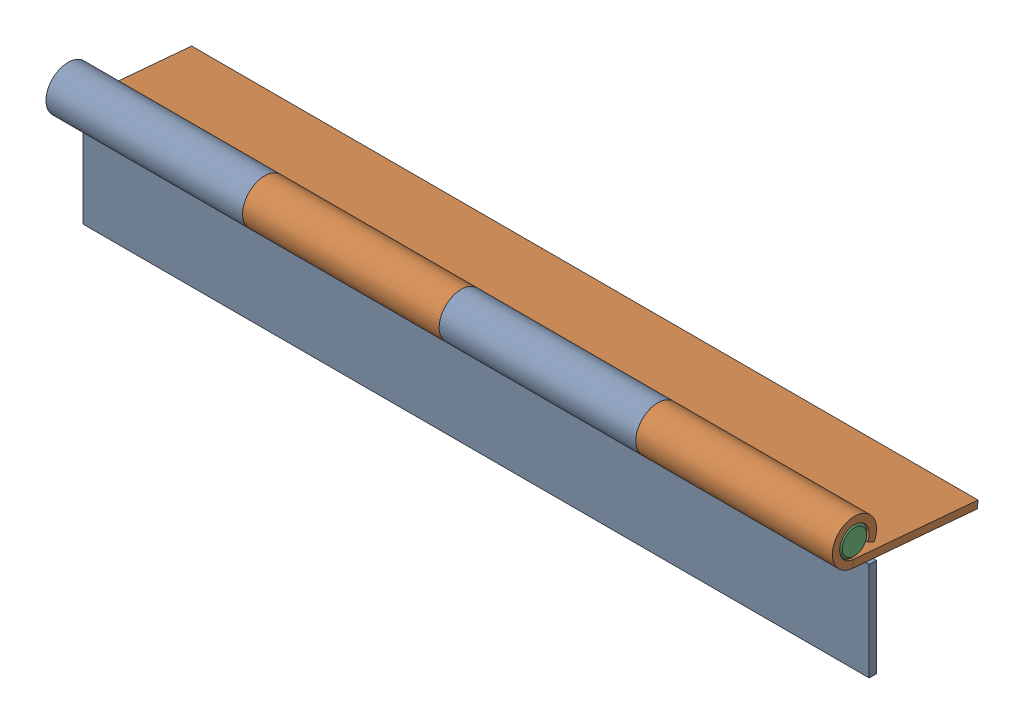
SolidWorks assembly MirrorMirrorBASE-Cabinet Hinge, configuration Default. Lengths in mm.
Overall size (160 30.38 30.67).
3 component instances, 2 part files, 3 mates.
Components (placement in the parent):
- MirrorMirrorBASE-Cabinet Hinge Flange-1: MirrorMirrorBASE-Cabinet Hinge Flange [Default] at (-155.1002 71.3389 114.9534) size (160 30 9)
- MirrorMirrorBASE-Cabinet Hinge Flange-2: MirrorMirrorBASE-Cabinet Hinge Flange [Default] at (4.8998 91.6279 92.8119) x (-1 0 0) z (0 0.996195 -0.087156) size (160 30 9)
- MirrorMirrorBASE-Cabinet Hinge Pin-1: MirrorMirrorBASE-Cabinet Hinge Pin [Default] at (-155.1002 93.2182 117.9534) x (0 0 -1) z (1 0 0) size (6 6 160)
Mates (geometry in assembly coordinates):
- Hinge1: hinge = 1.658063 rad: cylinder of assembly; plane of assembly; cylinder of assembly; plane of assembly; plane of assembly; plane of assembly; cylinder of MirrorMirrorBASE-Cabinet Hinge Flange-2 through (-75.1002 96.8389 117.9534) axis (1 0 0) radius 4.5; cylinder of MirrorMirrorBASE-Cabinet Hinge Flange-1 through (-75.1002 96.8389 117.9534) axis (-1 0 0) radius 4.5; plane of MirrorMirrorBASE-Cabinet Hinge Flange-2 through (-75.1002 96.8389 117.9534) normal (1 0 0); plane of MirrorMirrorBASE-Cabinet Hinge Flange-1 through (-75.1002 96.8389 117.9534) normal (-1 0 0); plane of MirrorMirrorBASE-Cabinet Hinge Flange-2 through (4.8998 90.1336 92.9427) normal (0 -0.996195 0.087156); plane of MirrorMirrorBASE-Cabinet Hinge Flange-1 through (-155.1002 71.3389 113.4534) normal (0 0 -1)
- Concentric1: concentric: cylinder of assembly; cylinder of assembly; cylinder of MirrorMirrorBASE-Cabinet Hinge Flange-2 through (4.8998 96.8389 117.9534) axis (1 0 0) radius 3; cylinder of MirrorMirrorBASE-Cabinet Hinge Pin-1 through (4.8998 96.8389 117.9534) axis (-1 0 0) radius 3
- Coincident1: coincident: plane of assembly; plane of assembly; plane of MirrorMirrorBASE-Cabinet Hinge Flange-2 through (4.8998 96.8389 117.9534) normal (1 0 0); plane of MirrorMirrorBASE-Cabinet Hinge Pin-1 through (4.8998 96.8389 117.9534) normal (1 0 0)
